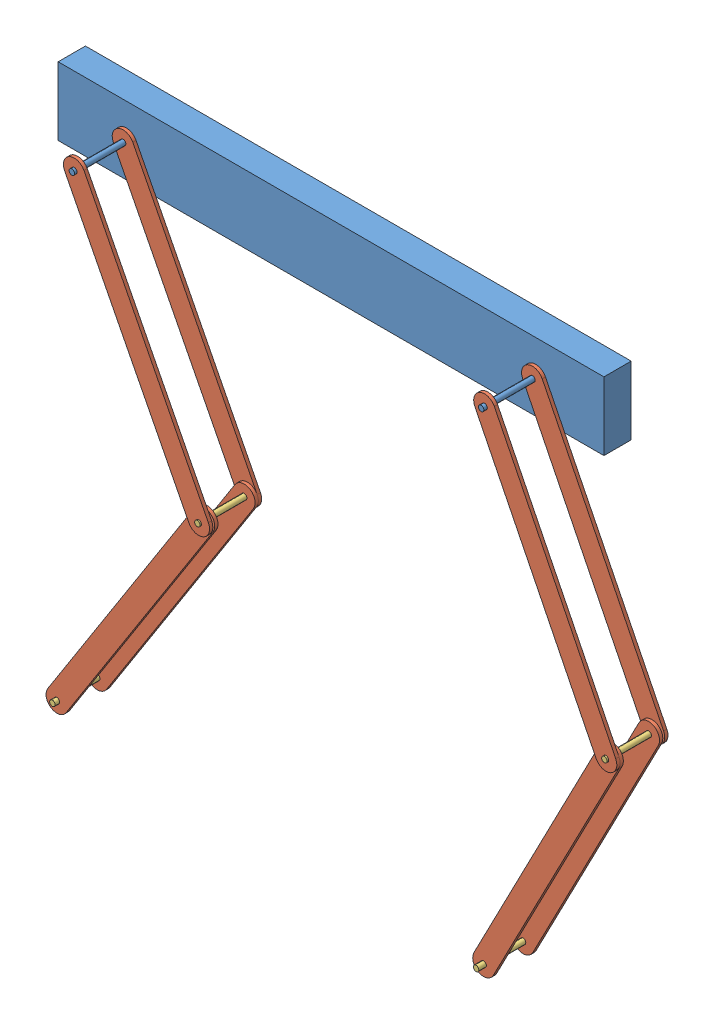
SolidWorks assembly Assem1, configuration Default. Lengths in mm.
Overall size (263.63 196.36 30.31).
13 component instances, 3 part files, 28 mates.
Components (placement in the parent):
- Part2P-1: Part2P [Default] at (-1468.0987 -1557.9398 142.5216) size (200 25 30)
- Partp-1: Partp [Default] at (131.2933 -62.3353 142.5216) x (0.998044 -0.062516 0) z (0 0 1) size (58 94.6 1.2)
- Partp-2: Partp [Default] at (-16.4737 -62.4361 142.5216) x (0.998734 -0.050305 0) z (0 0 1) size (58 94.6 1.2)
- Partp-3: Partp [Default] at (-16.4737 -62.4361 160.4091) x (0.998734 -0.050305 0) z (0 0 1) size (58 94.6 1.2)
- Partp-4: Partp [Default] at (131.2933 -62.3353 160.0647) x (0.998044 -0.062516 0) z (0 0 1) size (58 94.6 1.2)
- Part5-1: Part5 [Default] at (22.7129 21.128 142.0782) x (0.99991 0.01345 0) z (0 0 1) size (2 2 20)
- Partp-5: Partp [Default] at (-125.0245 -54.8394 143.7216) x (0.460632 -0.887591 0) z (0 0 1) size (58 94.6 1.2)
- Partp-6: Partp [Default] at (-125.0245 -54.8394 158.5202) x (0.460632 -0.887591 0) z (0 0 1) size (58 94.6 1.2)
- Part5-2: Part5 [Default] at (-32.3626 -44.965 141.3677) x (0.42729 -0.904115 0) z (0 0 1) size (2 2 20)
- Partp-7: Partp [Default] at (32.2802 -69.5549 158.8647) x (0.538651 -0.842529 0) z (0 0 1) size (58 94.6 1.2)
- Partp-8: Partp [Default] at (32.2802 -69.5549 144.4159) x (0.538651 -0.842529 0) z (0 0 1) size (58 94.6 1.2)
- Part5-3: Part5 [Default] at (124.2445 -50.2115 142.8301) x (0.43899 -0.898492 0) z (0 0 1) size (2 2 20)
- Part5-4: Part5 [Default] at (170.6127 22.0985 141.8369) x (0.995496 -0.0948 0) z (0 0 1) size (2 2 20)
Mates (geometry in assembly coordinates):
- Concentric1: concentric aligned: circle of Part2P-1; circle of Partp-1
- Concentric2: concentric aligned: circle of Part2P-1; circle of Partp-2
- Concentric3: concentric aligned: circle of Part2P-1; circle of Partp-3
- Parallel4: parallel anti-aligned: line of Partp-2 through (-12.9097 118.3662 143.7216) axis (0.455801 -0.890082 0); line of Partp-3 through (39.7911 33.0045 160.4091) axis (-0.455801 0.890082 0)
- Concentric4: concentric anti-aligned: circle of Part2P-1; circle of Partp-4
- Parallel5: parallel aligned: line of Partp-1 through (137.0683 118.4099 143.7216) axis (0.444881 -0.89559 0); line of Partp-4 through (137.0683 118.4099 160.0647) axis (0.444881 -0.89559 0)
- Concentric5: concentric aligned: circle of Partp-3; circle of Partp-5
- Concentric6: concentric aligned: circle of Partp-3; circle of Part5-1
- Concentric7: concentric aligned: circle of Part5-1; circle of Partp-6
- Parallel6: parallel aligned: line of Partp-5 through (32.8599 33.3347 144.9216) axis (-0.53836 -0.842715 0); line of Partp-6 through (32.8599 33.3347 159.7202) axis (-0.53836 -0.842715 0)
- Concentric8: concentric anti-aligned: circle of Partp-6; circle of Part5-2
- Lock1: lock: unknown of Partp-5; unknown of Part5-2
- Lock2: lock: unknown of Partp-6; unknown of Part5-2
- Lock3: lock: unknown of Partp-3; unknown of Part5-1
- Lock4: lock: unknown of Partp-2; unknown of Part5-1
- Concentric9: concentric anti-aligned: cylinder of Partp-4; cylinder of Partp-8 through (185.1388 30.6304 144.4159) axis (0 0 -1) radius 1.01
- Concentric10: concentric aligned: circle of Partp-4; cylinder of Partp-7 through (185.1388 30.6304 158.8647) axis (0 0 -1) radius 1.01
- Parallel11: parallel aligned: line of Partp-7 through (142.6572 -59.9858 158.8647) axis (0.460326 0.88775 0); line of Partp-8 through (142.6572 -59.9858 145.6159) axis (0.460326 0.88775 0)
- Concentric11: concentric aligned: circle of Partp-1; circle of Part5-4
- Concentric12: concentric aligned: circle of Partp-8; circle of Part5-3
- Lock5: lock: unknown of Partp-4; unknown of Part5-4
- Lock6: lock: unknown of Partp-1; unknown of Part5-4
- Lock7: lock: unknown of Partp-7; unknown of Part5-3
- Lock8: lock: unknown of Partp-8; unknown of Part5-3
- Coincident6: coincident anti-aligned: plane of Partp-4 through (162.8947 75.4099 160.0647) normal (0 0 -1); plane of Partp-7 through (162.1225 -13.7571 160.0647) normal (0 0 1)
- Coincident7: coincident anti-aligned: plane of Part2P-1 through (65.6507 120.1894 142.5216) normal (0 0 1); plane of Partp-1 through (162.8947 75.4099 142.5216) normal (0 0 -1)
- Coincident8: coincident anti-aligned: plane of Part2P-1 through (65.6507 120.1894 142.5216) normal (0 0 1); plane of Partp-2 through (13.4407 75.6853 142.5216) normal (0 0 -1)
- Coincident9: coincident anti-aligned: plane of Partp-2 through (13.4407 75.6853 143.7216) normal (0 0 1); plane of Partp-5 through (9.3128 -10.9545 143.7216) normal (0 0 -1)
